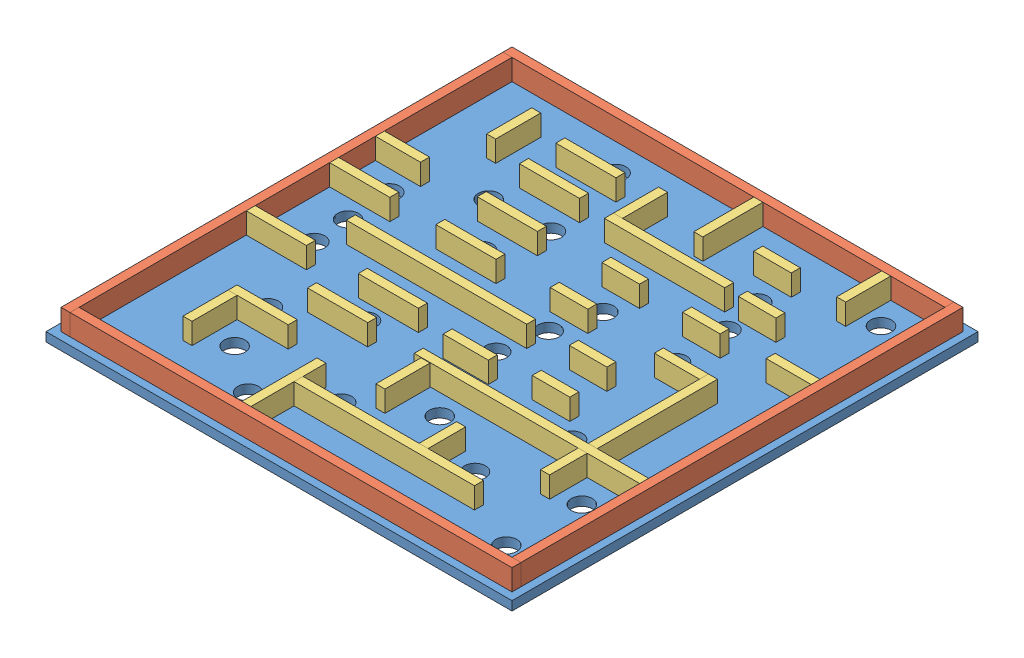
SolidWorks assembly Final Maze, configuration Default. Lengths in mm.
Overall size (310 20 310).
40 component instances, 3 part files, 80 mates.
Components (placement in the parent):
- BaseBoxAssly-1: BaseBoxAssly [Default] at (-12.8705 -1.2268 2.8694) size (310 20 310)
  - BasePlate-1: BasePlate [Default] at (-151.1959 -24.6494 167.7009) size (310 6 310)
  - SIdePlate-1: SIdePlate [Default] at (147.8041 -18.6494 9.7009) x (0 0 -1) z (1 0 0) size (294 20 6)
  - SIdePlate-2: SIdePlate [Default] at (0.8041 -18.6494 -131.2991) x (-1 0 0) z (0 0 -1) size (294 20 6)
  - SIdePlate-3: SIdePlate [Default] at (-140.1959 -18.6494 15.7009) x (0 0 1) z (-1 0 0) size (294 20 6)
  - SIdePlate-4: SIdePlate [Default] at (6.8041 -18.6494 156.7009) size (294 20 6)
- Partition-4: Partition [Default] at (-123.0664 -19.8762 -43.5576) x (0 0 1) z (-1 0 0) size (6 20 30)
- Partition-5: Partition [Width_40mm] at (-113.0664 -19.8762 -13.1242) x (0 0 1) z (-1 0 0) size (6 20 40)
- Partition-6: Partition [Default] at (98.9101 -19.8762 -98.4297) x (-1 0 0) z (0 0 -1) size (6 20 30)
- Partition-7: Partition [Width_40mm] at (13.8528 -19.8762 -88.4297) x (-1 0 0) z (0 0 -1) size (6 20 40)
- Partition-8: Partition [Width_80mm] at (-29.5858 -19.8762 -66.4297) x (0 0 -1) z (1 0 0) size (6 20 80)
- Partition-9: Partition [Default] at (-23.5858 -19.8762 -72.4297) x (-1 0 0) z (0 0 -1) size (6 20 30)
- Partition-10: Partition [Width_25mm] at (59.9026 -19.8762 -66.0237) x (0 0 -1) z (1 0 0) size (6 20 25)
- Partition-11: Partition [Width_40mm] at (-89.1006 -19.8762 -93.5969) x (0 0 -1) z (1 0 0) size (6 20 40)
- Partition-12: Partition [Width_40mm] at (-89.3437 -19.8762 -69.6289) x (0 0 -1) z (1 0 0) size (6 20 40)
- Partition-13: Partition [Default] at (-117.4457 -19.8762 -105.9367) size (6 20 30)
- Partition-14: Partition [Width_40mm] at (-84.3152 -19.8762 -36.5882) x (0 0 -1) z (1 0 0) size (6 20 40)
- Partition-15: Partition [Width_25mm] at (64.0443 -19.8762 -103.1133) x (0 0 1) z (-1 0 0) size (6 20 25)
- Partition-16: Partition [Width_40mm] at (-42.0611 -19.8762 -12.7416) x (0 0 1) z (-1 0 0) size (6 20 40)
- Partition-17: Partition [Width_25mm] at (20.0145 -19.8762 -46.1832) x (0 0 1) z (-1 0 0) size (6 20 25)
- Partition-18: Partition [Width_25mm] at (75.501 -19.8762 -44.3092) x (0 0 1) z (-1 0 0) size (6 20 25)
- Partition-19: Partition [Width_25mm] at (17.2195 -19.8762 -14.5483) x (0 0 1) z (-1 0 0) size (6 20 25)
- Partition-20: Partition [Default] at (134.9336 -19.8762 -45.4515) x (0 0 1) z (-1 0 0) size (6 20 30)
- Partition-21: Partition [Width_40mm] at (-113.0664 -19.8762 42.3562) x (0 0 1) z (-1 0 0) size (6 20 40)
- Partition-22: Partition [Default] at (94.6976 -19.8762 -11.3692) x (0 0 1) z (-1 0 0) size (6 20 30)
- Partition-23: Partition [Width_150mm] at (134.9336 -19.8762 68.6308) x (0 0 1) z (-1 0 0) size (6 20 150)
- Partition-24: Partition [Width_25mm] at (56.9154 -19.8762 12.442) x (0 0 1) z (-1 0 0) size (6 20 25)
- Partition-25: Partition [Width_25mm] at (61.8985 -19.8762 42.0917) x (0 0 1) z (-1 0 0) size (6 20 25)
- Partition-26: Partition [Default] at (13.471 -19.8762 47.8817) x (0 0 1) z (-1 0 0) size (6 20 30)
- Partition-27: Partition [Width_40mm] at (-39.654 -19.8762 41.2451) x (0 0 1) z (-1 0 0) size (6 20 40)
- Partition-28: Partition [Width_40mm] at (-48.2464 -19.8762 66.4158) x (0 0 1) z (-1 0 0) size (6 20 40)
- Partition-29: Partition [Width_40mm] at (-73.4214 -19.8762 94.09) x (0 0 1) z (-1 0 0) size (6 20 40)
- Partition-31: Partition [Width_120mm] at (81.2448 -19.8762 124.851) x (0 0 1) z (-1 0 0) size (6 20 120)
- Partition-32: Partition [Width_120mm] at (5.582 -19.8762 14.4421) x (0 0 1) z (-1 0 0) size (6 20 120)
- Partition-41: Partition [Default] at (-107.4214 -19.8762 130.09) x (-1 0 0) z (0 0 -1) size (6 20 30)
- Partition-42: Partition [width_50mm] at (-38.7552 -19.8762 159.5703) x (-1 0 0) z (0 0 -1) size (6 20 50)
- Partition-43: Partition [Width_25mm] at (44.3808 -19.8762 124.851) x (-1 0 0) z (0 0 -1) size (6 20 25)
- Partition-44: Partition [Width_25mm] at (100.0043 -19.8762 99.6308) x (-1 0 0) z (0 0 -1) size (6 20 25)
- Partition-45: Partition [Default] at (-4.2324 -19.8762 104.917) x (-1 0 0) z (0 0 -1) size (6 20 30)
- Partition-46: Partition [Width_80mm] at (100.6976 -19.8762 68.6308) x (-1 0 0) z (0 0 -1) size (6 20 80)
Mates (geometry in assembly coordinates):
- Coincident1: coincident anti-aligned: plane of BaseBoxAssly-1/BasePlate-1 through (-164.0664 -19.8762 170.5703) normal (0 1 0); plane of Partition-4 through (-153.0664 -19.8762 -43.5576) normal (0 -1 0)
- Coincident2: coincident anti-aligned: plane of BaseBoxAssly-1/SIdePlate-3 through (-153.0664 -19.8762 18.5703) normal (1 0 0); plane of Partition-4 through (-153.0664 -19.8762 -43.5576) normal (-1 0 0)
- Coincident3: coincident anti-aligned: plane of BaseBoxAssly-1/BasePlate-1 through (-164.0664 -19.8762 170.5703) normal (0 1 0); plane of Partition-5 through (-153.0664 -19.8762 -13.1242) normal (0 -1 0)
- Coincident4: coincident anti-aligned: plane of BaseBoxAssly-1/SIdePlate-3 through (-153.0664 -19.8762 18.5703) normal (1 0 0); plane of Partition-5 through (-153.0664 -19.8762 -13.1242) normal (-1 0 0)
- Coincident5: coincident anti-aligned: plane of BaseBoxAssly-1/BasePlate-1 through (-164.0664 -19.8762 170.5703) normal (0 1 0); plane of Partition-6 through (98.9101 -19.8762 -128.4297) normal (0 -1 0)
- Coincident6: coincident anti-aligned: plane of BaseBoxAssly-1/SIdePlate-2 through (-12.0664 -19.8762 -128.4297) normal (0 0 1); plane of Partition-6 through (98.9101 -19.8762 -128.4297) normal (0 0 -1)
- Coincident7: coincident anti-aligned: plane of BaseBoxAssly-1/BasePlate-1 through (-164.0664 -19.8762 170.5703) normal (0 1 0); plane of Partition-7 through (13.8528 -19.8762 -128.4297) normal (0 -1 0)
- Coincident8: coincident anti-aligned: plane of BaseBoxAssly-1/SIdePlate-2 through (-12.0664 -19.8762 -128.4297) normal (0 0 1); plane of Partition-7 through (13.8528 -19.8762 -128.4297) normal (0 0 -1)
- Coincident9: coincident anti-aligned: plane of BaseBoxAssly-1/BasePlate-1 through (-164.0664 -19.8762 170.5703) normal (0 1 0); plane of Partition-8 through (50.4142 -19.8762 -66.4297) normal (0 -1 0)
- Parallel2: parallel anti-aligned: plane of BaseBoxAssly-1/SIdePlate-2 through (-12.0664 -19.8762 -128.4297) normal (0 0 1); plane of Partition-8 through (50.4142 -19.8762 -72.4297) normal (0 0 -1)
- Coincident10: coincident anti-aligned: plane of BaseBoxAssly-1/BasePlate-1 through (-164.0664 -19.8762 170.5703) normal (0 1 0); plane of Partition-9 through (-23.5858 -19.8762 -102.4297) normal (0 -1 0)
- Distance1: distance = 56 mm anti-aligned: plane of Partition-8 through (50.4142 -19.8762 -72.4297) normal (0 0 -1); plane of BaseBoxAssly-1/SIdePlate-2 through (-12.0664 -19.8762 -128.4297) normal (0 0 1)
- Coincident12: coincident anti-aligned: plane of Partition-8 through (50.4142 -19.8762 -72.4297) normal (0 0 -1); plane of Partition-9 through (-23.5858 -19.8762 -72.4297) normal (0 0 1)
- Coincident13: coincident aligned: plane of Partition-8 through (-29.5858 -19.8762 -66.4297) normal (-1 0 0); plane of Partition-9 through (-29.5858 -19.8762 -102.4297) normal (-1 0 0)
- Coincident15: coincident anti-aligned: plane of BaseBoxAssly-1/BasePlate-1 through (-164.0664 -19.8762 170.5703) normal (0 1 0); plane of Partition-10 through (84.9026 -19.8762 -66.0237) normal (0 -1 0)
- Parallel3: parallel anti-aligned: plane of BaseBoxAssly-1/SIdePlate-2 through (-12.0664 -19.8762 -128.4297) normal (0 0 1); plane of Partition-10 through (84.9026 -19.8762 -72.0237) normal (0 0 -1)
- Coincident16: coincident anti-aligned: plane of BaseBoxAssly-1/BasePlate-1 through (-164.0664 -19.8762 170.5703) normal (0 1 0); plane of Partition-11 through (-49.1006 -19.8762 -93.5969) normal (0 -1 0)
- Parallel4: parallel anti-aligned: plane of BaseBoxAssly-1/SIdePlate-2 through (-12.0664 -19.8762 -128.4297) normal (0 0 1); plane of Partition-11 through (-49.1006 -19.8762 -99.5969) normal (0 0 -1)
- Coincident17: coincident anti-aligned: plane of BaseBoxAssly-1/BasePlate-1 through (-164.0664 -19.8762 170.5703) normal (0 1 0); plane of Partition-12 through (-49.3437 -19.8762 -69.6289) normal (0 -1 0)
- Coincident18: coincident anti-aligned: plane of BaseBoxAssly-1/BasePlate-1 through (-164.0664 -19.8762 170.5703) normal (0 1 0); plane of Partition-13 through (-117.4457 -19.8762 -75.9367) normal (0 -1 0)
- Parallel5: parallel anti-aligned: plane of BaseBoxAssly-1/SIdePlate-3 through (-153.0664 -19.8762 18.5703) normal (1 0 0); plane of Partition-13 through (-117.4457 -19.8762 -75.9367) normal (-1 0 0)
- Coincident19: coincident anti-aligned: plane of BaseBoxAssly-1/BasePlate-1 through (-164.0664 -19.8762 170.5703) normal (0 1 0); plane of Partition-14 through (-44.3152 -19.8762 -36.5882) normal (0 -1 0)
- Coincident20: coincident anti-aligned: plane of BaseBoxAssly-1/BasePlate-1 through (-164.0664 -19.8762 170.5703) normal (0 1 0); plane of Partition-15 through (39.0443 -19.8762 -103.1133) normal (0 -1 0)
- Parallel6: parallel anti-aligned: plane of BaseBoxAssly-1/SIdePlate-2 through (-12.0664 -19.8762 -128.4297) normal (0 0 1); plane of Partition-15 through (39.0443 -19.8762 -103.1133) normal (0 0 -1)
- Coincident22: coincident anti-aligned: plane of BaseBoxAssly-1/BasePlate-1 through (-164.0664 -19.8762 170.5703) normal (0 1 0); plane of Partition-16 through (-82.0611 -19.8762 -12.7416) normal (0 -1 0)
- Parallel7: parallel anti-aligned: plane of BaseBoxAssly-1/SIdePlate-2 through (-12.0664 -19.8762 -128.4297) normal (0 0 1); plane of Partition-16 through (-82.0611 -19.8762 -12.7416) normal (0 0 -1)
- Coincident24: coincident anti-aligned: plane of BaseBoxAssly-1/BasePlate-1 through (-164.0664 -19.8762 170.5703) normal (0 1 0); plane of Partition-17 through (-4.9855 -19.8762 -46.1832) normal (0 -1 0)
- Parallel8: parallel anti-aligned: plane of BaseBoxAssly-1/SIdePlate-2 through (-12.0664 -19.8762 -128.4297) normal (0 0 1); plane of Partition-17 through (-4.9855 -19.8762 -46.1832) normal (0 0 -1)
- Coincident26: coincident anti-aligned: plane of BaseBoxAssly-1/BasePlate-1 through (-164.0664 -19.8762 170.5703) normal (0 1 0); plane of Partition-18 through (50.501 -19.8762 -44.3092) normal (0 -1 0)
- Parallel9: parallel anti-aligned: plane of BaseBoxAssly-1/SIdePlate-2 through (-12.0664 -19.8762 -128.4297) normal (0 0 1); plane of Partition-18 through (50.501 -19.8762 -44.3092) normal (0 0 -1)
- Coincident28: coincident anti-aligned: plane of BaseBoxAssly-1/BasePlate-1 through (-164.0664 -19.8762 170.5703) normal (0 1 0); plane of Partition-19 through (-7.7805 -19.8762 -14.5483) normal (0 -1 0)
- Parallel10: parallel anti-aligned: plane of BaseBoxAssly-1/SIdePlate-2 through (-12.0664 -19.8762 -128.4297) normal (0 0 1); plane of Partition-19 through (-7.7805 -19.8762 -14.5483) normal (0 0 -1)
- Coincident30: coincident anti-aligned: plane of BaseBoxAssly-1/BasePlate-1 through (-164.0664 -19.8762 170.5703) normal (0 1 0); plane of Partition-20 through (104.9336 -19.8762 -45.4515) normal (0 -1 0)
- Parallel11: parallel anti-aligned: plane of BaseBoxAssly-1/SIdePlate-2 through (-12.0664 -19.8762 -128.4297) normal (0 0 1); plane of Partition-20 through (104.9336 -19.8762 -45.4515) normal (0 0 -1)
- Coincident32: coincident anti-aligned: plane of BaseBoxAssly-1/BasePlate-1 through (-164.0664 -19.8762 170.5703) normal (0 1 0); plane of Partition-21 through (-153.0664 -19.8762 42.3562) normal (0 -1 0)
- Parallel12: parallel anti-aligned: plane of BaseBoxAssly-1/SIdePlate-2 through (-12.0664 -19.8762 -128.4297) normal (0 0 1); plane of Partition-21 through (-153.0664 -19.8762 42.3562) normal (0 0 -1)
- Coincident33: coincident anti-aligned: plane of BaseBoxAssly-1/BasePlate-1 through (-164.0664 -19.8762 170.5703) normal (0 1 0); plane of Partition-22 through (64.6976 -19.8762 -11.3692) normal (0 -1 0)
- Parallel13: parallel anti-aligned: plane of BaseBoxAssly-1/SIdePlate-2 through (-12.0664 -19.8762 -128.4297) normal (0 0 1); plane of Partition-22 through (64.6976 -19.8762 -11.3692) normal (0 0 -1)
- Coincident34: coincident anti-aligned: plane of BaseBoxAssly-1/BasePlate-1 through (-164.0664 -19.8762 170.5703) normal (0 1 0); plane of Partition-23 through (-15.0664 -19.8762 68.6308) normal (0 -1 0)
- Parallel14: parallel anti-aligned: plane of BaseBoxAssly-1/SIdePlate-2 through (-12.0664 -19.8762 -128.4297) normal (0 0 1); plane of Partition-23 through (-15.0664 -19.8762 68.6308) normal (0 0 -1)
- Coincident35: coincident anti-aligned: plane of BaseBoxAssly-1/BasePlate-1 through (-164.0664 -19.8762 170.5703) normal (0 1 0); plane of Partition-24 through (31.9154 -19.8762 12.442) normal (0 -1 0)
- Parallel15: parallel anti-aligned: plane of BaseBoxAssly-1/SIdePlate-2 through (-12.0664 -19.8762 -128.4297) normal (0 0 1); plane of Partition-24 through (31.9154 -19.8762 12.442) normal (0 0 -1)
- Coincident36: coincident anti-aligned: plane of BaseBoxAssly-1/BasePlate-1 through (-164.0664 -19.8762 170.5703) normal (0 1 0); plane of Partition-25 through (36.8985 -19.8762 42.0917) normal (0 -1 0)
- Parallel16: parallel anti-aligned: plane of BaseBoxAssly-1/SIdePlate-2 through (-12.0664 -19.8762 -128.4297) normal (0 0 1); plane of Partition-25 through (36.8985 -19.8762 42.0917) normal (0 0 -1)
- Coincident37: coincident anti-aligned: plane of BaseBoxAssly-1/BasePlate-1 through (-164.0664 -19.8762 170.5703) normal (0 1 0); plane of Partition-26 through (-16.529 -19.8762 47.8817) normal (0 -1 0)
- Parallel17: parallel anti-aligned: plane of BaseBoxAssly-1/SIdePlate-2 through (-12.0664 -19.8762 -128.4297) normal (0 0 1); plane of Partition-26 through (-16.529 -19.8762 47.8817) normal (0 0 -1)
- Coincident38: coincident anti-aligned: plane of BaseBoxAssly-1/BasePlate-1 through (-164.0664 -19.8762 170.5703) normal (0 1 0); plane of Partition-27 through (-79.654 -19.8762 41.2451) normal (0 -1 0)
- Parallel18: parallel anti-aligned: plane of BaseBoxAssly-1/SIdePlate-2 through (-12.0664 -19.8762 -128.4297) normal (0 0 1); plane of Partition-27 through (-79.654 -19.8762 41.2451) normal (0 0 -1)
- Coincident39: coincident anti-aligned: plane of BaseBoxAssly-1/BasePlate-1 through (-164.0664 -19.8762 170.5703) normal (0 1 0); plane of Partition-28 through (-88.2464 -19.8762 66.4158) normal (0 -1 0)
- Parallel19: parallel anti-aligned: plane of BaseBoxAssly-1/SIdePlate-2 through (-12.0664 -19.8762 -128.4297) normal (0 0 1); plane of Partition-28 through (-88.2464 -19.8762 66.4158) normal (0 0 -1)
- Coincident40: coincident anti-aligned: plane of BaseBoxAssly-1/BasePlate-1 through (-164.0664 -19.8762 170.5703) normal (0 1 0); plane of Partition-29 through (-113.4214 -19.8762 94.09) normal (0 -1 0)
- Parallel20: parallel anti-aligned: plane of BaseBoxAssly-1/SIdePlate-2 through (-12.0664 -19.8762 -128.4297) normal (0 0 1); plane of Partition-29 through (-113.4214 -19.8762 94.09) normal (0 0 -1)
- Coincident42: coincident anti-aligned: plane of BaseBoxAssly-1/BasePlate-1 through (-164.0664 -19.8762 170.5703) normal (0 1 0); plane of Partition-31 through (-38.7552 -19.8762 124.851) normal (0 -1 0)
- Parallel22: parallel anti-aligned: plane of BaseBoxAssly-1/SIdePlate-2 through (-12.0664 -19.8762 -128.4297) normal (0 0 1); plane of Partition-31 through (-38.7552 -19.8762 124.851) normal (0 0 -1)
- Coincident43: coincident anti-aligned: plane of BaseBoxAssly-1/BasePlate-1 through (-164.0664 -19.8762 170.5703) normal (0 1 0); plane of Partition-32 through (-114.418 -19.8762 14.4421) normal (0 -1 0)
- Parallel23: parallel anti-aligned: plane of BaseBoxAssly-1/SIdePlate-2 through (-12.0664 -19.8762 -128.4297) normal (0 0 1); plane of Partition-32 through (-114.418 -19.8762 14.4421) normal (0 0 -1)
- Coincident59: coincident anti-aligned: plane of BaseBoxAssly-1/BasePlate-1 through (-164.0664 -19.8762 170.5703) normal (0 1 0); plane of Partition-41 through (-107.4214 -19.8762 100.09) normal (0 -1 0)
- Parallel26: parallel anti-aligned: plane of BaseBoxAssly-1/SIdePlate-2 through (-12.0664 -19.8762 -128.4297) normal (0 0 1); plane of Partition-41 through (-107.4214 -19.8762 100.09) normal (0 0 -1)
- Coincident60: coincident anti-aligned: plane of BaseBoxAssly-1/BasePlate-1 through (-164.0664 -19.8762 170.5703) normal (0 1 0); plane of Partition-42 through (-38.7552 -19.8762 109.5703) normal (0 -1 0)
- Parallel27: parallel anti-aligned: plane of BaseBoxAssly-1/SIdePlate-2 through (-12.0664 -19.8762 -128.4297) normal (0 0 1); plane of Partition-42 through (-38.7552 -19.8762 109.5703) normal (0 0 -1)
- Coincident61: coincident anti-aligned: plane of BaseBoxAssly-1/BasePlate-1 through (-164.0664 -19.8762 170.5703) normal (0 1 0); plane of Partition-43 through (44.3808 -19.8762 99.851) normal (0 -1 0)
- Parallel28: parallel anti-aligned: plane of BaseBoxAssly-1/SIdePlate-2 through (-12.0664 -19.8762 -128.4297) normal (0 0 1); plane of Partition-43 through (44.3808 -19.8762 99.851) normal (0 0 -1)
- Coincident62: coincident anti-aligned: plane of BaseBoxAssly-1/BasePlate-1 through (-164.0664 -19.8762 170.5703) normal (0 1 0); plane of Partition-44 through (100.0043 -19.8762 74.6308) normal (0 -1 0)
- Parallel29: parallel anti-aligned: plane of BaseBoxAssly-1/SIdePlate-2 through (-12.0664 -19.8762 -128.4297) normal (0 0 1); plane of Partition-44 through (100.0043 -19.8762 74.6308) normal (0 0 -1)
- Coincident63: coincident anti-aligned: plane of BaseBoxAssly-1/BasePlate-1 through (-164.0664 -19.8762 170.5703) normal (0 1 0); plane of Partition-45 through (-4.2324 -19.8762 74.917) normal (0 -1 0)
- Parallel30: parallel anti-aligned: plane of BaseBoxAssly-1/SIdePlate-2 through (-12.0664 -19.8762 -128.4297) normal (0 0 1); plane of Partition-45 through (-4.2324 -19.8762 74.917) normal (0 0 -1)
- Coincident64: coincident anti-aligned: plane of BaseBoxAssly-1/BasePlate-1 through (-164.0664 -19.8762 170.5703) normal (0 1 0); plane of Partition-46 through (100.6976 -19.8762 -11.3692) normal (0 -1 0)
- Parallel31: parallel anti-aligned: plane of BaseBoxAssly-1/SIdePlate-2 through (-12.0664 -19.8762 -128.4297) normal (0 0 1); plane of Partition-46 through (100.6976 -19.8762 -11.3692) normal (0 0 -1)
- Coincident66: coincident anti-aligned: plane of BaseBoxAssly-1/SIdePlate-1 through (134.9336 -19.8762 12.5703) normal (-1 0 0); plane of Partition-20 through (134.9336 -19.8762 -45.4515) normal (1 0 0)
- Coincident67: coincident anti-aligned: plane of Partition-29 through (-113.4214 -19.8762 100.09) normal (0 0 1); plane of Partition-41 through (-107.4214 -19.8762 100.09) normal (0 0 -1)
- Coincident68: coincident aligned: plane of Partition-29 through (-113.4214 -19.8762 94.09) normal (-1 0 0); plane of Partition-41 through (-113.4214 -19.8762 100.09) normal (-1 0 0)
- Coincident69: coincident anti-aligned: plane of BaseBoxAssly-1/SIdePlate-4 through (-6.0664 -19.8762 159.5703) normal (0 0 -1); plane of Partition-42 through (-38.7552 -19.8762 159.5703) normal (0 0 1)
- Coincident70: coincident anti-aligned: plane of Partition-31 through (-38.7552 -19.8762 124.851) normal (-1 0 0); plane of Partition-42 through (-38.7552 -19.8762 109.5703) normal (1 0 0)
- Coincident71: coincident anti-aligned: plane of Partition-31 through (-38.7552 -19.8762 124.851) normal (0 0 -1); plane of Partition-43 through (44.3808 -19.8762 124.851) normal (0 0 1)
- Coincident72: coincident anti-aligned: plane of BaseBoxAssly-1/SIdePlate-3 through (-153.0664 -19.8762 18.5703) normal (1 0 0); plane of Partition-21 through (-153.0664 -19.8762 42.3562) normal (-1 0 0)
- Coincident73: coincident anti-aligned: plane of BaseBoxAssly-1/SIdePlate-1 through (134.9336 -19.8762 12.5703) normal (-1 0 0); plane of Partition-23 through (134.9336 -19.8762 68.6308) normal (1 0 0)
- Coincident74: coincident anti-aligned: plane of Partition-23 through (-15.0664 -19.8762 74.6308) normal (0 0 1); plane of Partition-44 through (100.0043 -19.8762 74.6308) normal (0 0 -1)
- Coincident75: coincident anti-aligned: plane of Partition-23 through (-15.0664 -19.8762 68.6308) normal (0 0 -1); plane of Partition-46 through (100.6976 -19.8762 68.6308) normal (0 0 1)
- Coincident76: coincident anti-aligned: plane of Partition-22 through (94.6976 -19.8762 -11.3692) normal (1 0 0); plane of Partition-46 through (94.6976 -19.8762 -11.3692) normal (-1 0 0)
- Coincident77: coincident aligned: plane of Partition-22 through (64.6976 -19.8762 -11.3692) normal (0 0 -1); plane of Partition-46 through (100.6976 -19.8762 -11.3692) normal (0 0 -1)
